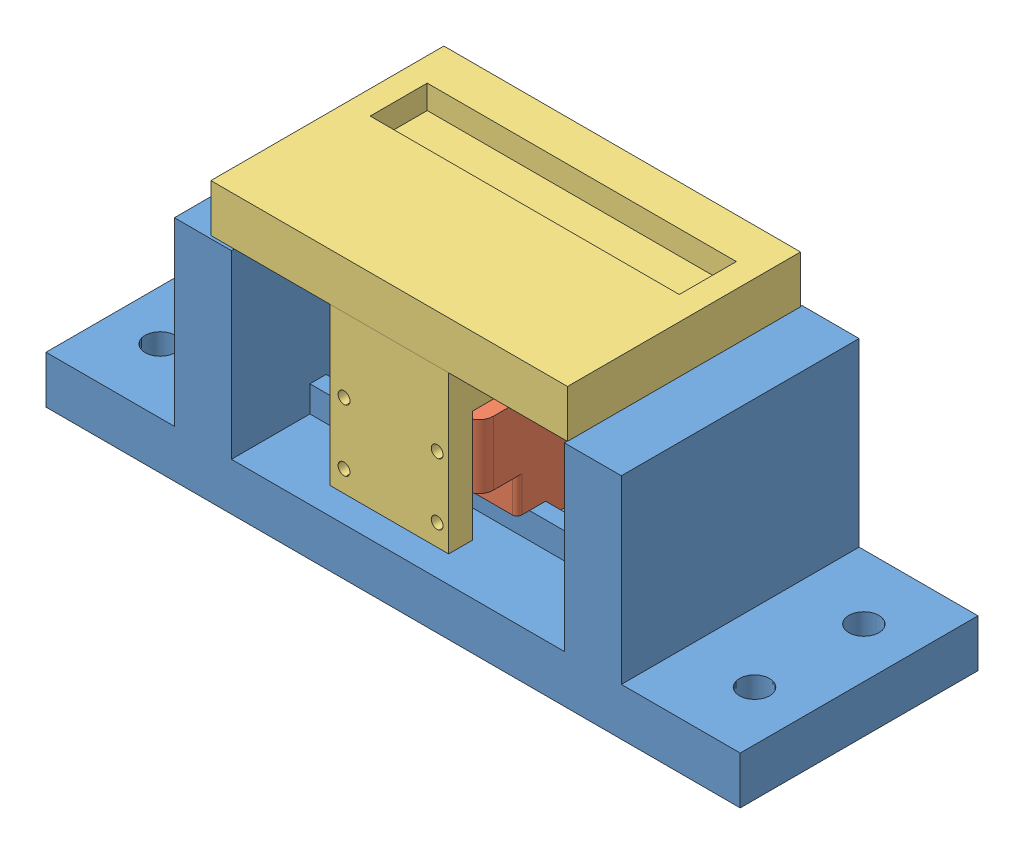
SolidWorks assembly lead screw assembled, configuration Default. Lengths in mm.
Overall size (146 58.5 50).
3 component instances, 3 part files, 5 mates.
Components (placement in the parent):
- Lead screw-1: Lead screw [Default] at (-2.128 85.1737 135.8453) size (146 48 50)
- Lead screw platform-1: Lead screw platform [Default] at (57.4474 100.6737 179.9453) size (25.59 26.17 38.2)
- OCT mount-1: OCT mount [Default] at (57.4474 121.6737 180.2453) size (75 43 49)
Mates (geometry in assembly coordinates):
- Concentric1: concentric aligned: cylinder of Lead screw-1 through (30.6495 115.3737 160.8453) axis (1 0 0) radius 2.2; cylinder of Lead screw platform-1 through (51.2249 115.3737 160.8453) axis (1 0 0) radius 2.2
- Coincident2: coincident anti-aligned: plane of Lead screw-1 through (106.872 97.4737 165.9453) normal (0 0 -1); plane of Lead screw platform-1 through (57.4474 97.4737 165.9453) normal (0 0 1)
- Concentric2: concentric aligned: cylinder of Lead screw platform-1 through (60.4474 118.1437 146.7453) axis (0 0 -1) radius 1.25; cylinder of OCT mount-1 through (60.4474 118.1437 146.7453) axis (0 0 -1) radius 1.25
- Coincident3: coincident anti-aligned: plane of Lead screw platform-1 through (57.4474 121.6437 141.7453) normal (0 0 -1); plane of OCT mount-1 through (57.4474 100.6737 141.7453) normal (0 0 1)
- Concentric3: concentric aligned: cylinder of Lead screw platform-1 through (60.4474 105.1737 146.7453) axis (0 0 -1) radius 1.25; cylinder of OCT mount-1 through (60.4474 105.1737 146.7453) axis (0 0 -1) radius 1.25
